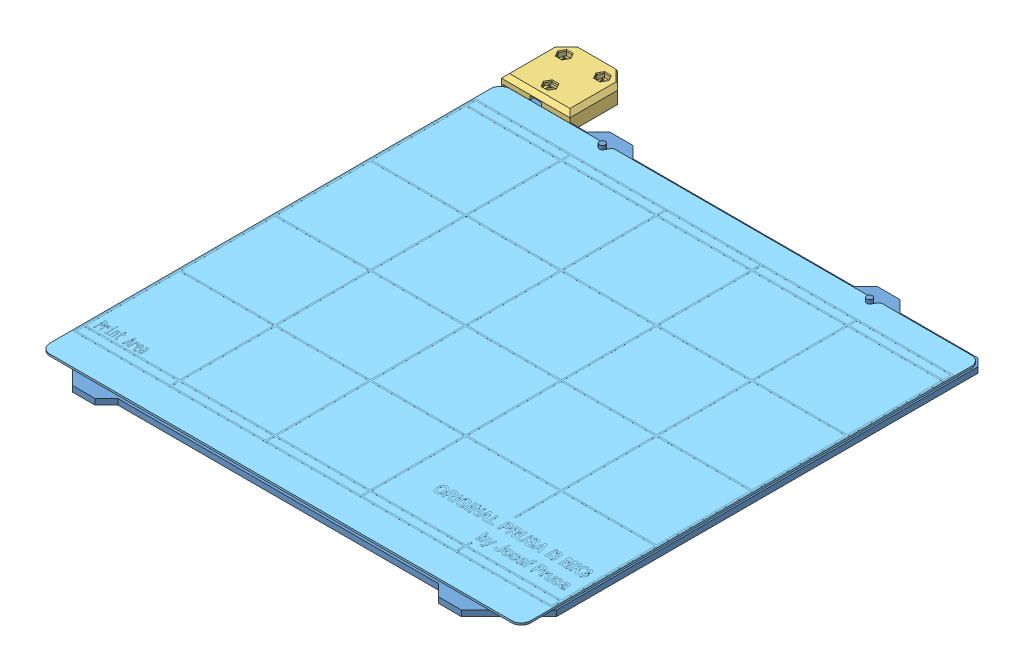
SolidWorks assembly Headbed Assembly, configuration Default. Lengths in mm.
Overall size (253.8 13.6 281.4).
13 component instances, 5 part files, 28 mates.
Components (placement in the parent):
- MK52 Bed-1: MK52 Bed [Default] at (-64.502 153.1745 327.7347) size (253.8 6 264.25)
- 6x6x3t spacer-1: 6x6x3t spacer [Default] at (62.498 147.1745 212.6933) size (6 6 6)
- 6x6x3t spacer-2: 6x6x3t spacer [Default] at (62.498 147.1745 107.6933) size (6 6 6)
- 6x6x3t spacer-3: 6x6x3t spacer [Default] at (-47.502 147.1745 317.6933) size (6 6 6)
- 6x6x3t spacer-4: 6x6x3t spacer [Default] at (-47.502 147.1745 107.6933) x (0.97497 0 -0.222336) z (0.222336 0 0.97497) size (6 6 6)
- 6x6x3t spacer-5: 6x6x3t spacer [Default] at (167.498 147.1745 317.6933) size (6 6 6)
- 6x6x3t spacer-6: 6x6x3t spacer [Default] at (167.498 147.1745 212.6933) size (6 6 6)
- 6x6x3t spacer-7: 6x6x3t spacer [Default] at (167.498 147.1745 107.6933) x (0.999855 0 0.017002) z (-0.017002 0 0.999855) size (6 6 6)
- 6x6x3t spacer-8: 6x6x3t spacer [Default] at (62.498 147.1745 317.6933) size (6 6 6)
- 6x6x3t spacer-9: 6x6x3t spacer [Default] at (-47.502 147.1745 212.6933) size (6 6 6)
- heatbed-cable-cover top-1: heatbed-cable-cover top [Default] at (-46.0021 152.1745 93.2347) x (1 0 0) z (0 1 0) size (36 32 8.6)
- heatbed-cable-cover bottom-1: heatbed-cable-cover bottom [Default] at (-46.0021 157.6745 113.2347) x (-1 0 0) z (0 -1 0) size (30 16.5 6)
- SS Sheet-1: SS Sheet [Default] at (-63.6476 156.1745 335.43) size (252 1.01 241)
Mates (geometry in assembly coordinates):
- Concentric1: concentric anti-aligned: circle of MK52 Bed-1; cylinder of 6x6x3t spacer-3 through (-47.502 153.1745 317.6933) axis (0 -1 0) radius 1.75
- Concentric2: concentric anti-aligned: circle of MK52 Bed-1; cylinder of 6x6x3t spacer-8 through (62.498 153.1745 317.6933) axis (0 -1 0) radius 1.75
- Concentric3: concentric anti-aligned: cylinder of MK52 Bed-1 through (167.498 153.1745 317.6933) axis (0 1 0) radius 1.55; cylinder of 6x6x3t spacer-5 through (167.498 153.1745 317.6933) axis (0 -1 0) radius 1.75
- Concentric4: concentric anti-aligned: circle of MK52 Bed-1; circle of 6x6x3t spacer-9
- Concentric5: concentric anti-aligned: circle of MK52 Bed-1; circle of 6x6x3t spacer-1
- Concentric6: concentric aligned: circle of MK52 Bed-1; circle of 6x6x3t spacer-6
- Concentric7: concentric anti-aligned: circle of MK52 Bed-1; circle of 6x6x3t spacer-4
- Concentric8: concentric anti-aligned: circle of MK52 Bed-1; circle of 6x6x3t spacer-2
- Concentric9: concentric aligned: circle of MK52 Bed-1; circle of 6x6x3t spacer-7
- Coincident1: coincident anti-aligned: plane of MK52 Bed-1 through (-64.502 153.1745 327.7347) normal (0 -1 0); plane of 6x6x3t spacer-8 through (62.498 153.1745 317.6933) normal (0 1 0)
- Coincident2: coincident anti-aligned: plane of MK52 Bed-1 through (-64.502 153.1745 327.7347) normal (0 -1 0); plane of 6x6x3t spacer-5 through (167.498 153.1745 317.6933) normal (0 1 0)
- Coincident3: coincident anti-aligned: plane of MK52 Bed-1 through (-64.502 153.1745 327.7347) normal (0 -1 0); plane of 6x6x3t spacer-3 through (-47.502 153.1745 317.6933) normal (0 1 0)
- Coincident4: coincident anti-aligned: plane of MK52 Bed-1 through (-64.502 153.1745 327.7347) normal (0 -1 0); plane of 6x6x3t spacer-9 through (-47.502 153.1745 212.6933) normal (0 1 0)
- Coincident5: coincident anti-aligned: plane of MK52 Bed-1 through (-64.502 153.1745 327.7347) normal (0 -1 0); plane of 6x6x3t spacer-1 through (62.498 153.1745 212.6933) normal (0 1 0)
- Coincident6: coincident anti-aligned: plane of MK52 Bed-1 through (-64.502 153.1745 327.7347) normal (0 -1 0); plane of 6x6x3t spacer-2 through (62.498 153.1745 107.6933) normal (0 1 0)
- Coincident7: coincident anti-aligned: plane of MK52 Bed-1 through (-64.502 153.1745 327.7347) normal (0 -1 0); plane of 6x6x3t spacer-6 through (167.498 153.1745 212.6933) normal (0 1 0)
- Coincident8: coincident anti-aligned: plane of MK52 Bed-1 through (-64.502 153.1745 327.7347) normal (0 -1 0); plane of 6x6x3t spacer-4 through (-47.502 153.1745 107.6933) normal (0 1 0)
- Coincident9: coincident anti-aligned: plane of MK52 Bed-1 through (-64.502 153.1745 327.7347) normal (0 -1 0); plane of 6x6x3t spacer-7 through (167.498 153.1745 107.6933) normal (0 1 0)
- Concentric10: concentric aligned: circle of MK52 Bed-1; cylinder of heatbed-cable-cover top-1 through (-46.0021 155.1745 85.7347) axis (0 1 0) radius 1.6
- Concentric11: concentric anti-aligned: cylinder of heatbed-cable-cover top-1 through (-56.0021 152.1745 68.2347) axis (0 1 0) radius 1.6; circle of heatbed-cable-cover bottom-1
- Concentric12: concentric aligned: cylinder of heatbed-cable-cover top-1 through (-36.0021 152.1745 68.2347) axis (0 1 0) radius 1.6; cylinder of heatbed-cable-cover bottom-1 through (-36.0021 149.1745 68.2347) axis (0 1 0) radius 1.6
- Coincident10: coincident anti-aligned: plane of MK52 Bed-1 through (-64.502 156.1745 327.7347) normal (0 1 0); plane of heatbed-cable-cover top-1 through (-32.0021 156.1745 97.2347) normal (0 -1 0)
- Parallel1: parallel aligned: plane of MK52 Bed-1 through (-64.402 156.1745 327.7347) normal (-1 0 0); plane of heatbed-cable-cover top-1 through (-64.0021 152.1745 93.2347) normal (-1 0 0)
- Parallel2: parallel aligned: plane of heatbed-cable-cover top-1 through (-64.0021 152.1745 93.2347) normal (-1 0 0); plane of heatbed-cable-cover bottom-1 through (-61.0021 149.1745 77.7347) normal (-1 0 0)
- Coincident12: coincident anti-aligned: plane of heatbed-cable-cover top-1 through (-61.0021 155.1745 78.2347) normal (0 -1 0); plane of heatbed-cable-cover bottom-1 through (-61.0021 155.1745 77.7347) normal (0 1 0)
- Coincident13: coincident: plane of MK52 Bed-1 through (-64.502 156.1745 327.7347) normal (0 1 0); plane of SS Sheet-1 through (-63.6476 156.1745 336.7794) normal (0 -1 0)
- Coincident16: coincident: plane of MK52 Bed-1 through (62.498 153.1745 327.7347) normal (-1 0 0); plane of SS Sheet-1 through (62.498 156.1745 336.7794) normal (-1 0 0)
- Tangent1: tangent anti-aligned: cylinder of MK52 Bed-1 through (-7.502 159.1745 96.7347) axis (0 -1 0) radius 1.55; plane of SS Sheet-1 through (-63.6476 156.1745 98.2847) normal (0 0 -1)
